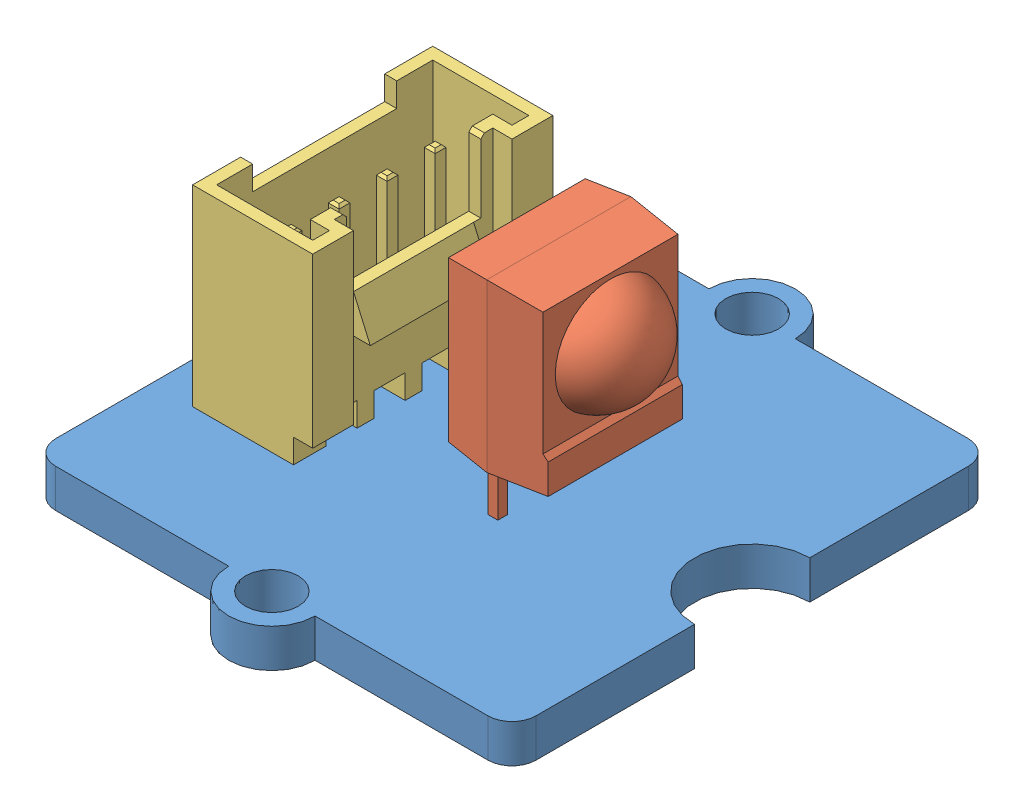
SolidWorks assembly Grove Infrared Sensor, configuration Défaut. Lengths in mm.
Overall size (20 11.7 23.6).
3 component instances, 3 part files, 6 mates.
Components (placement in the parent):
- PCB grove 20x20-1: PCB grove 20x20 [Défaut] at (-0.787 -0.8532 23.6) size (20 1.6 23.6)
- Recepteur-1: Recepteur [Défaut] at (1.163 6.7468 23.6) x (0 0 -1) z (1 0 0) size (6 10.7 5.7)
- Connecteur Grove (droit)-1: Connecteur Grove (droit) [Défaut] at (-4.087 0.7468 23.6) x (0 0 -1) z (1 0 0) size (10 11 5)
Mates (geometry in assembly coordinates):
- Coïncidente1: coincident anti-aligned: plane of PCB grove 20x20-1 through (-0.787 0.7468 23.6) normal (0 1 0); plane of Connecteur Grove (droit)-1 through (-4.087 0.7468 23.6) normal (0 -1 0)
- Coïncidente2: coincident anti-aligned: plane of PCB grove 20x20-1 through (-0.787 -0.8532 23.6) normal (0 0 1); plane of Connecteur Grove (droit)-1 through (-4.087 0.7468 23.6) normal (0 0 -1)
- Coïncidente3: coincident anti-aligned: plane of PCB grove 20x20-1 through (-0.787 -0.8532 23.6) normal (0 0 1); plane of Recepteur-1 through (1.163 6.7468 23.6) normal (0 0 -1)
- Distance1: distance = 6 mm aligned: plane of Recepteur-1 through (1.163 6.7468 23.6) normal (0 1 0); plane of PCB grove 20x20-1 through (-0.787 0.7468 23.6) normal (0 1 0)
- Distance2: distance = 1.7 mm aligned: plane of PCB grove 20x20-1 through (-10.787 0.7468 23.6) normal (-1 0 0); plane of Connecteur Grove (droit)-1 through (-9.087 8.7468 28.6) normal (-1 0 0)
- Distance3: distance = 10.2 mm aligned: plane of Recepteur-1 through (-0.587 6.7468 23.6) normal (-1 0 0); plane of PCB grove 20x20-1 through (-10.787 0.7468 23.6) normal (-1 0 0)
